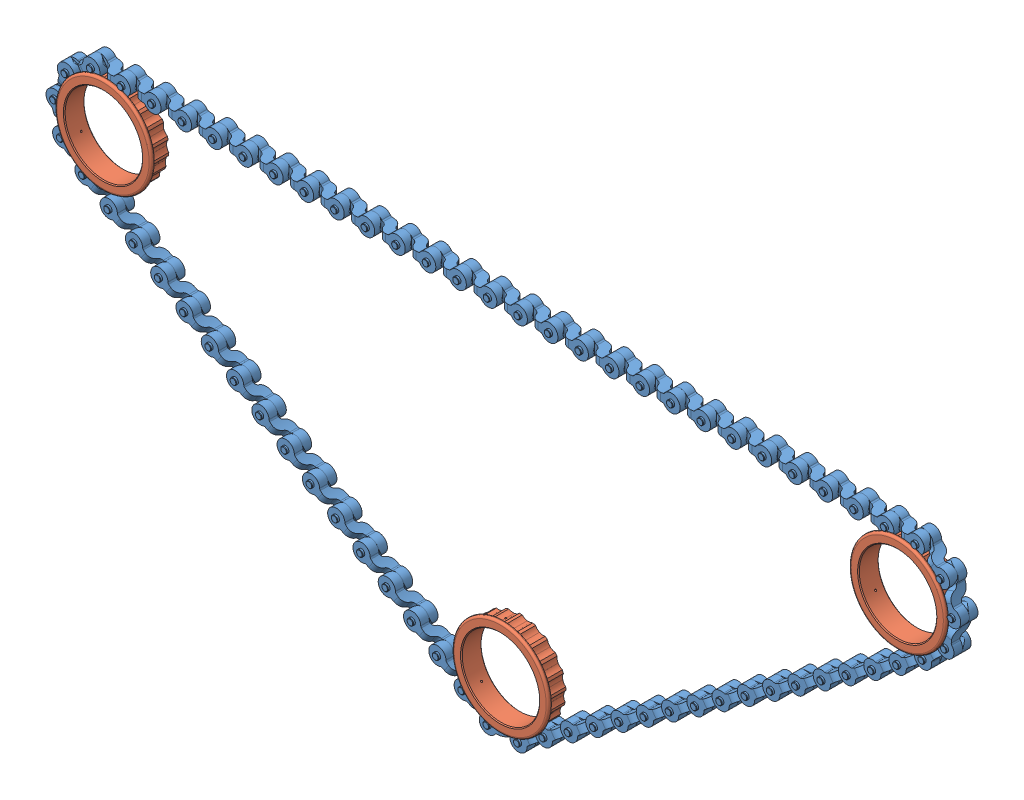
SolidWorks assembly MirrorchainLink03, configuration Default. Lengths in mm.
Overall size (1353.31 582.01 30.16).
71 component instances, 2 part files, 0 mates.
Components (placement in the parent):
- Mirrorlink03-1: Mirrorlink03 [with_dowell] at origin size (70.32 25.4 25.4)
- MirrorRing03-1: MirrorRing03 [Default] at origin size (162.8 162.8 30.16)
- Mirrorlink03-2: Mirrorlink03 [with_dowell] at (41.0225 -12.6555 0) x (0.826197 -0.563382 0) z (0 0 1) size (70.32 25.4 25.4)
- Mirrorlink03-3: Mirrorlink03 [Default] at (67.7853 -46.2227 0) x (0.365202 -0.930928 0) z (0 0 1) size (70.32 25.4 25.4)
- Mirrorlink03-4: Mirrorlink03 [with_dowell] at (70.9855 -89.0335 0) x (-0.22274 -0.974878 0) z (0 0 1) size (70.32 25.4 25.4)
- Mirrorlink03-5: Mirrorlink03 [with_dowell] at (-44.92 0 0) size (70.32 25.4 25.4)
- Mirrorlink03-6: Mirrorlink03 [Default] at (-89.84 0 0) size (70.32 25.4 25.4)
- Mirrorlink03-7: Mirrorlink03 [with_dowell] at (-134.76 0 0) size (70.32 25.4 25.4)
- Mirrorlink03-8: Mirrorlink03 [with_dowell] at (-179.68 0 0) size (70.32 25.4 25.4)
- Mirrorlink03-9: Mirrorlink03 [with_dowell] at (-224.6 0 0) size (70.32 25.4 25.4)
- Mirrorlink03-10: Mirrorlink03 [Default] at (-269.52 0 0) size (70.32 25.4 25.4)
- Mirrorlink03-11: Mirrorlink03 [with_dowell] at (-314.44 0 0) size (70.32 25.4 25.4)
- Mirrorlink03-12: Mirrorlink03 [with_dowell] at (-359.36 0 0) size (70.32 25.4 25.4)
- Mirrorlink03-13: Mirrorlink03 [with_dowell] at (-404.28 0 0) size (70.32 25.4 25.4)
- Mirrorlink03-14: Mirrorlink03 [Default] at (-449.2 0 0) size (70.32 25.4 25.4)
- Mirrorlink03-15: Mirrorlink03 [with_dowell] at (-494.12 0 0) size (70.32 25.4 25.4)
- Mirrorlink03-16: Mirrorlink03 [with_dowell] at (-539.04 0 0) size (70.32 25.4 25.4)
- Mirrorlink03-17: Mirrorlink03 [with_dowell] at (49.5106 -126.2066 0) x (-0.733255 -0.679953 0) z (0 0 1) size (70.32 25.4 25.4)
- Mirrorlink03-18: Mirrorlink03 [with_dowell] at (14.4475 -154.0761 0) x (-0.827884 -0.560899 0) z (0 0 1) size (70.32 25.4 25.4)
- Mirrorlink03-19: Mirrorlink03 [Default] at (-22.741 -179.2717 0) x (-0.827884 -0.560899 0) z (0 0 1) size (70.32 25.4 25.4)
- Mirrorlink03-20: Mirrorlink03 [with_dowell] at (-59.9296 -204.4672 0) x (-0.827884 -0.560899 0) z (0 0 1) size (70.32 25.4 25.4)
- Mirrorlink03-21: Mirrorlink03 [with_dowell] at (-97.1181 -229.6628 0) x (-0.827884 -0.560899 0) z (0 0 1) size (70.32 25.4 25.4)
- Mirrorlink03-22: Mirrorlink03 [with_dowell] at (-134.3067 -254.8584 0) x (-0.827884 -0.560899 0) z (0 0 1) size (70.32 25.4 25.4)
- Mirrorlink03-23: Mirrorlink03 [Default] at (-171.4953 -280.054 0) x (-0.827884 -0.560899 0) z (0 0 1) size (70.32 25.4 25.4)
- Mirrorlink03-24: Mirrorlink03 [with_dowell] at (-208.6838 -305.2496 0) x (-0.827884 -0.560899 0) z (0 0 1) size (70.32 25.4 25.4)
- Mirrorlink03-25: Mirrorlink03 [with_dowell] at (-245.8724 -330.4452 0) x (-0.827884 -0.560899 0) z (0 0 1) size (70.32 25.4 25.4)
- Mirrorlink03-26: Mirrorlink03 [with_dowell] at (-283.0609 -355.6408 0) x (-0.827884 -0.560899 0) z (0 0 1) size (70.32 25.4 25.4)
- Mirrorlink03-27: Mirrorlink03 [Default] at (-320.2495 -380.8364 0) x (-0.827884 -0.560899 0) z (0 0 1) size (70.32 25.4 25.4)
- Mirrorlink03-28: Mirrorlink03 [with_dowell] at (-357.438 -406.032 0) x (-0.827884 -0.560899 0) z (0 0 1) size (70.32 25.4 25.4)
- Mirrorlink03-29: Mirrorlink03 [with_dowell] at (-394.6266 -431.2275 0) x (-0.827884 -0.560899 0) z (0 0 1) size (70.32 25.4 25.4)
- Mirrorlink03-30: Mirrorlink03 [with_dowell] at (-431.8151 -456.4231 0) x (-0.827884 -0.560899 0) z (0 0 1) size (70.32 25.4 25.4)
- Mirrorlink03-31: Mirrorlink03 [with_dowell] at (-583.96 0 0) size (70.32 25.4 25.4)
- Mirrorlink03-32: Mirrorlink03 [Default] at (-469.0037 -481.6187 0) x (-0.827884 -0.560899 0) z (0 0 1) size (70.32 25.4 25.4)
- Mirrorlink03-33: Mirrorlink03 [with_dowell] at (-506.1923 -506.8143 0) x (-0.827884 -0.560899 0) z (0 0 1) size (70.32 25.4 25.4)
- Mirrorlink03-34: Mirrorlink03 [Default] at (-628.88 0 0) size (70.32 25.4 25.4)
- Mirrorlink03-35: Mirrorlink03 [with_dowell] at (-673.8 0 0) size (70.32 25.4 25.4)
- Mirrorlink03-36: Mirrorlink03 [with_dowell] at (-718.72 0 0) size (70.32 25.4 25.4)
- Mirrorlink03-37: Mirrorlink03 [with_dowell] at (-763.64 0 0) size (70.32 25.4 25.4)
- Mirrorlink03-38: Mirrorlink03 [Default] at (-808.56 0 0) size (70.32 25.4 25.4)
- Mirrorlink03-39: Mirrorlink03 [with_dowell] at (-853.48 0 0) size (70.32 25.4 25.4)
- Mirrorlink03-40: Mirrorlink03 [with_dowell] at (-898.4 0 0) size (70.32 25.4 25.4)
- Mirrorlink03-41: Mirrorlink03 [with_dowell] at (-943.32 0 0) size (70.32 25.4 25.4)
- Mirrorlink03-42: Mirrorlink03 [Default] at (-988.24 0 0) size (70.32 25.4 25.4)
- Mirrorlink03-43: Mirrorlink03 [with_dowell] at (-1033.16 0 0) size (70.32 25.4 25.4)
- Mirrorlink03-44: Mirrorlink03 [with_dowell] at (-1078.08 0 0) size (70.32 25.4 25.4)
- Mirrorlink03-45: Mirrorlink03 [with_dowell] at (-1123 0 0) size (70.32 25.4 25.4)
- MirrorRing03-2: MirrorRing03 [Default] at (-1167.9198 0.1482 0) x (0.999978 -0.006595 0) z (0 0 1) size (162.8 162.8 30.16)
- Mirrorlink03-46: Mirrorlink03 [Default] at (-1167.9202 0.1481 0) x (0.999978 -0.006595 0) z (0 0 1) size (70.32 25.4 25.4)
- Mirrorlink03-47: Mirrorlink03 [with_dowell] at (-1209.0252 -12.2367 0) x (0.829894 0.557921 0) z (0 0 1) size (70.32 25.4 25.4)
- Mirrorlink03-48: Mirrorlink03 [with_dowell] at (-1236.0085 -45.6268 0) x (0.371333 0.9285 0) z (0 0 1) size (70.32 25.4 25.4)
- Mirrorlink03-49: Mirrorlink03 [with_dowell] at (-1239.4907 -88.4156 0) x (-0.216306 0.976326 0) z (0 0 1) size (70.32 25.4 25.4)
- Mirrorlink03-50: Mirrorlink03 [Default] at (-1218.2613 -125.7293 0) x (-0.728755 0.684774 0) z (0 0 1) size (70.32 25.4 25.4)
- Mirrorlink03-51: Mirrorlink03 [with_dowell] at (-1183.2993 -153.707 0) x (-0.827884 0.560899 0) z (0 0 1) size (70.32 25.4 25.4)
- Mirrorlink03-52: Mirrorlink03 [with_dowell] at (-1146.1107 -178.9026 0) x (-0.827884 0.560899 0) z (0 0 1) size (70.32 25.4 25.4)
- Mirrorlink03-53: Mirrorlink03 [with_dowell] at (-1108.9221 -204.0982 0) x (-0.827884 0.560899 0) z (0 0 1) size (70.32 25.4 25.4)
- Mirrorlink03-54: Mirrorlink03 [Default] at (-1071.7336 -229.2938 0) x (-0.827884 0.560899 0) z (0 0 1) size (70.32 25.4 25.4)
- Mirrorlink03-55: Mirrorlink03 [with_dowell] at (-1034.545 -254.4894 0) x (-0.827884 0.560899 0) z (0 0 1) size (70.32 25.4 25.4)
- Mirrorlink03-56: Mirrorlink03 [with_dowell] at (-997.3565 -279.685 0) x (-0.827884 0.560899 0) z (0 0 1) size (70.32 25.4 25.4)
- Mirrorlink03-57: Mirrorlink03 [with_dowell] at (-960.1679 -304.8806 0) x (-0.827884 0.560899 0) z (0 0 1) size (70.32 25.4 25.4)
- Mirrorlink03-58: Mirrorlink03 [Default] at (-922.9794 -330.0762 0) x (-0.827884 0.560899 0) z (0 0 1) size (70.32 25.4 25.4)
- Mirrorlink03-59: Mirrorlink03 [with_dowell] at (-885.7908 -355.2717 0) x (-0.827884 0.560899 0) z (0 0 1) size (70.32 25.4 25.4)
- Mirrorlink03-60: Mirrorlink03 [with_dowell] at (-848.6023 -380.4673 0) x (-0.827884 0.560899 0) z (0 0 1) size (70.32 25.4 25.4)
- Mirrorlink03-61: Mirrorlink03 [with_dowell] at (-811.4137 -405.6629 0) x (-0.827884 0.560899 0) z (0 0 1) size (70.32 25.4 25.4)
- Mirrorlink03-62: Mirrorlink03 [Default] at (-774.2251 -430.8585 0) x (-0.827884 0.560899 0) z (0 0 1) size (70.32 25.4 25.4)
- Mirrorlink03-63: Mirrorlink03 [with_dowell] at (-737.0366 -456.0541 0) x (-0.827884 0.560899 0) z (0 0 1) size (70.32 25.4 25.4)
- Mirrorlink03-64: Mirrorlink03 [with_dowell] at (-699.848 -481.2497 0) x (-0.827884 0.560899 0) z (0 0 1) size (70.32 25.4 25.4)
- Mirrorlink03-65: Mirrorlink03 [with_dowell] at (-662.6595 -506.4453 0) x (-0.827884 0.560899 0) z (0 0 1) size (70.32 25.4 25.4)
- MirrorRing03-3: MirrorRing03 [Default] at (-594.8073 -399.6616 0) x (0.989332 0.145676 0) z (0 0 1) size (162.8 162.8 30.16)
- Mirrorlink03-66: Mirrorlink03 [with_dowell] at (-543.3864 -532.0014 0) x (-0.828137 -0.560525 0) z (0 0 1) size (70.32 25.4 25.4)
- Mirrorlink03-67: Mirrorlink03 [with_dowell] at (-584.4462 -544.5156 0) x (-0.999994 0.003348 0) z (0 0 1) size (70.32 25.4 25.4)
- Mirrorlink03-68: Mirrorlink03 [Default] at (-625.4188 -531.7233 0) x (-0.824259 0.566213 0) z (0 0 1) size (70.32 25.4 25.4)
